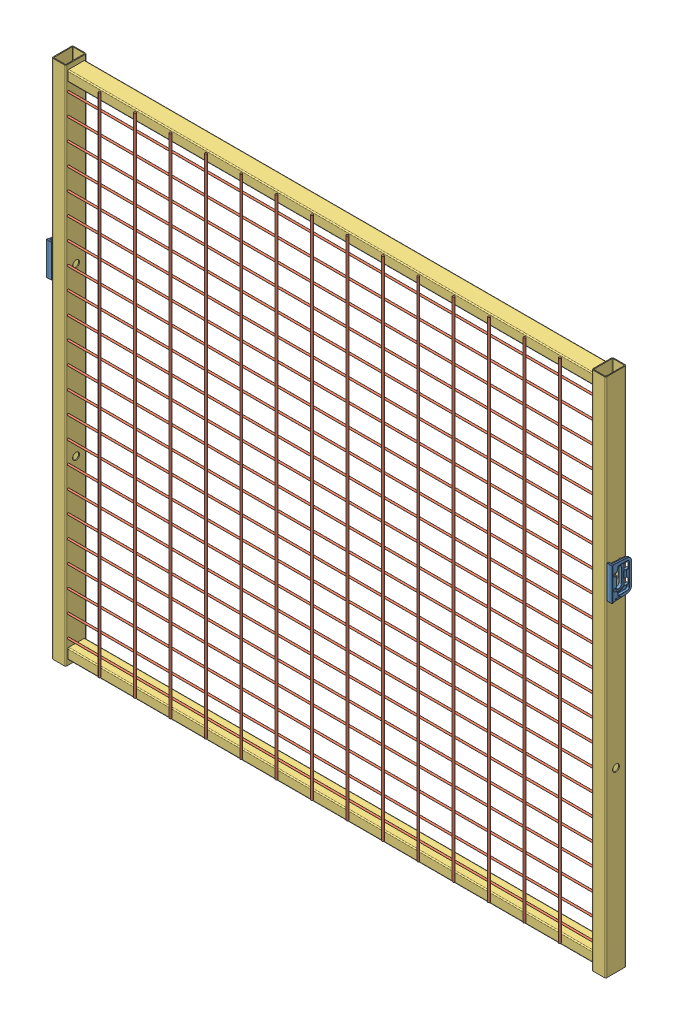
SolidWorks assembly W322-075080-Axelent, configuration Default. Lengths in mm.
Overall size (815.63 750 30).
4 component instances, 3 part files, 0 mates.
Components (placement in the parent):
- G2032-1: G2032 [Default] at (399 120 0) x (-1 0 0) z (0 0 1) size (9.31 48.01 29.42)
- G2032-2: G2032 [Default] at (-399 120 0) size (9.31 48.01 29.42)
- NÄT-50x30_III_N-05030-075-080-1: NÄT-50x30_III_N-05030-075-080 [Default] at (0 0 13.5) x (-1 0 0) z (0 0 -1) size (772 730 4.75)
- RAM-30_RAM-075-080-1: RAM-30_RAM-075-080 [Default] at origin size (798 750 30)
